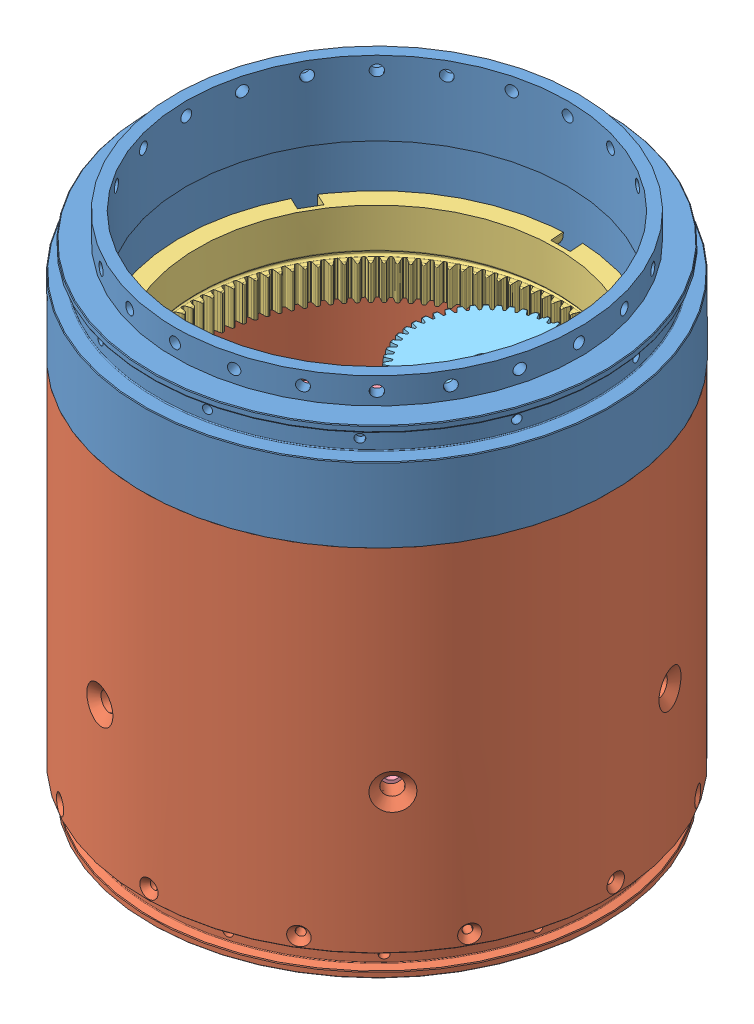
SolidWorks assembly Current_NCSR, configuration Default. Lengths in mm.
Overall size (210.02 182.47 210.02).
6 component instances, 6 part files, 10 mates.
Components (placement in the parent):
- Bottom_ring-1: Bottom_ring [Default] at (-17.9628 -24.3389 7.755) size (168.91 58.56 168.91)
- Top_ring-1: Top_ring [Default] at (-17.9628 -38.8774 7.755) x (0.999734 0 -0.023068) z (0.023068 0 0.999734) size (168.91 136.61 168.91)
- twist_coupling-1: twist_coupling [Default] at (-17.9628 -43.9273 7.755) x (0.563663 0 0.826005) z (-0.826005 0 0.563663) size (151.13 30.48 151.13)
- kepper ring-1: kepper ring [Default] at (-17.9628 -90.5838 7.755) x (-0.865391 0 -0.501097) z (0.501097 0 -0.865391) size (151.38 34.92 151.38)
- 7880K450_HT-LOAD MTL GEAR--20 DEG PRESSURE ANGLE-1: 7880K450_HT-LOAD MTL GEAR--20 DEG PRESSURE ANGLE [7880K45] at (-18.5718 -31.5448 -32.2404) x (-0.956557 0 -0.291544) z (0 1 0) size (52.9 52.9 14.26)
- Motor1_small-1: Motor1_small [Default] at (-18.5718 -74.6924 -32.2404) x (0 1 0) z (0.59958 0 0.800315) size (67.95 37.34 37.34)
Mates (geometry in assembly coordinates):
- Concentric3: concentric: cylinder of Bottom_ring-1 through (-17.9628 24.8045 7.755) axis (0 1 0) radius 71.4375; cylinder of Top_ring-1 through (-17.9628 -38.8774 7.755) axis (0 1 0) radius 76.2
- Parallel4: parallel: cylinder of Bottom_ring-1 through (-80.5974 9.658 -65.9596) axis (0 -1 0) radius 19.05; cylinder of Top_ring-1 through (-25.3687 -40.8179 -89.0711) axis (0 1 0) radius 19.05
- Concentric6: concentric: cylinder of Top_ring-1 through (-17.9628 -38.8774 7.755) axis (0 1 0) radius 76.2; cylinder of twist_coupling-1 through (-17.9628 16.8306 7.755) axis (0 1 0) radius 64.77
- Coincident2: coincident: plane of Top_ring-1 through (-19.7206 -28.3698 -68.4247) normal (0 -1 0); plane of twist_coupling-1 through (22.1249 -28.3698 66.5005) normal (0 1 0)
- Concentric8: concentric: cylinder of Top_ring-1 through (-17.9628 -38.8774 7.755) axis (0 1 0) radius 76.2; cylinder of kepper ring-1 through (-17.9628 -68.3588 7.755) axis (0 -1 0) radius 75.692
- Coincident3: coincident: plane of twist_coupling-1 through (24.6304 -37.8948 70.1721) normal (0 -1 0); plane of 7880K450_HT-LOAD MTL GEAR--20 DEG PRESSURE ANGLE-1 through (-18.5718 -37.8948 -32.2404) normal (0 -1 0)
- Concentric9: concentric: cylinder of 7880K450_HT-LOAD MTL GEAR--20 DEG PRESSURE ANGLE-1 through (-18.5718 -45.7688 -32.2404) axis (0 1 0) radius 3.9688; cylinder of Motor1_small-1 through (-18.5718 -112.3312 -32.2404) axis (0 -1 0) radius 1.5875
- Lock2: lock: unknown of Top_ring-1; unknown of 7880K450_HT-LOAD MTL GEAR--20 DEG PRESSURE ANGLE-1
- Concentric10: concentric: cylinder of Top_ring-1 through (44.5819 -85.6875 64.5072) axis (0.740568 0 0.671981) radius 3.2639; cylinder of kepper ring-1 through (38.0923 -85.6875 58.6186) axis (0.740568 0 0.671981) radius 2.5527
- Coincident5: coincident: plane of Bottom_ring-1 through (62.8092 -22.0198 7.755) normal (0 -1 0); plane of Top_ring-1 through (-19.6107 -22.0198 -63.6635) normal (0 1 0)
